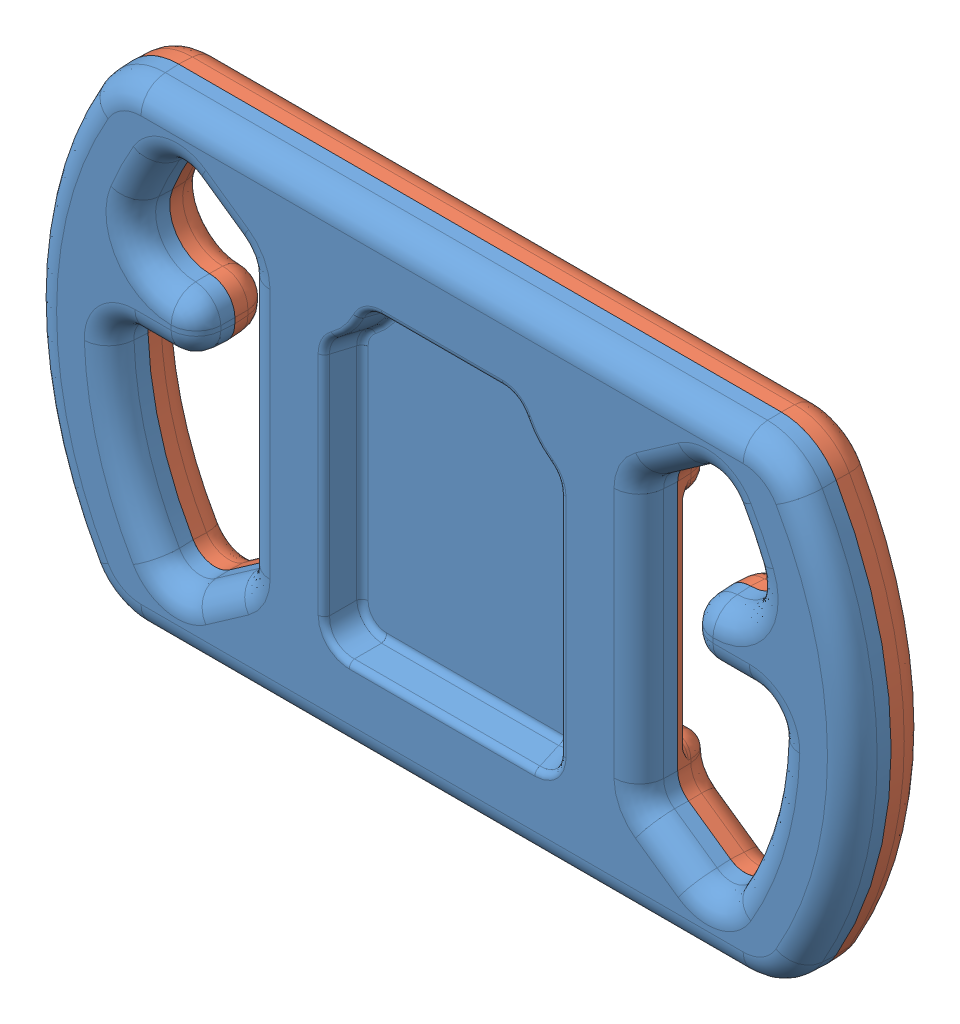
SolidWorks assembly PGR-5-01.95.100, configuration Domyślna. Lengths in mm.
Overall size (260 152.74 24.33).
2 component instances, 2 part files, 6 mates.
Components (placement in the parent):
- PGR-5-01.95.101-1: PGR-5-01.95.101 [Domyślna] at origin size (260 152.74 12)
- PGR-5-01.95.102-1: PGR-5-01.95.102 [Domyślna] x (-1 0 0) z (0 0 -1) size (260 152.74 12.75)
Mates (geometry in assembly coordinates):
- Wspólnie1: coincident aligned: plane of PGR-5-01.95.101-1 through (0 0 0) normal (0 0 1)
- Wspólnie2: coincident aligned: plane of PGR-5-01.95.101-1 through (0 0 0) normal (0 1 0)
- Wspólnie3: coincident aligned: plane of PGR-5-01.95.101-1 through (0 0 0) normal (1 0 0)
- Wspólnie4: coincident anti-aligned: plane of PGR-5-01.95.102-1 through (0 0 0) normal (0 0 -1)
- Wspólnie5: coincident aligned: plane of PGR-5-01.95.102-1 through (0 0 0) normal (0 1 0)
- Wspólnie6: coincident anti-aligned: plane of PGR-5-01.95.102-1 through (0 0 0) normal (-1 0 0)
